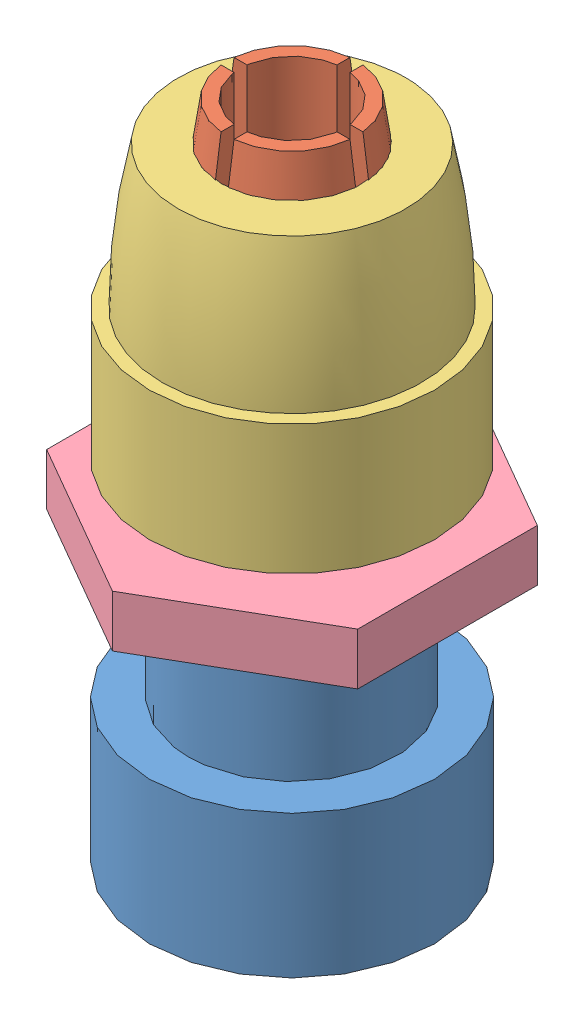
SolidWorks assembly Цанговый зажим, configuration По умолчанию. Lengths in mm.
Overall size (12 25.5 13.86).
4 component instances, 4 part files, 12 mates.
Components (placement in the parent):
- втулка-1: втулка [По умолчанию] at origin size (11 20 11)
- цанга-1: цанга [По умолчанию] at (0 10 0) size (6 15.5 6)
- прижимная гайка-1: прижимная гайка [По умолчанию] at (0 13.5 0) x (-1 0 0) z (0 0 -1) size (11 10.5 11)
- фиксирующая гайка-1: фиксирующая гайка [По умолчанию] at (0 12.5 0) x (1 0 0) z (0 -1 0) size (12 13.86 2)
Mates (geometry in assembly coordinates):
- Совпадение1: coincident anti-aligned: plane of втулка-1 through (5.5 0 0) normal (0 -1 0); plane of assembly through (0 0 0) normal (0 1 0)
- Совпадение2: coincident aligned: plane of втулка-1 through (0 0 0) normal (0 0 1); plane of assembly through (0 0 0) normal (0 0 1)
- Совпадение3: coincident aligned: plane of втулка-1 through (0 0 0) normal (1 0 0); plane of assembly through (0 0 0) normal (1 0 0)
- Концентричный1: concentric anti-aligned: cylinder of втулка-1 through (0 10 0) axis (0 1 0) radius 3; cylinder of цанга-1 through (0 10 0) axis (0 -1 0) radius 3
- Совпадение4: coincident anti-aligned: plane of втулка-1 through (0 10 0) normal (0 1 0); plane of цанга-1 through (3 10 0) normal (0 -1 0)
- Совпадение5: coincident aligned: plane of цанга-1 through (0 10 0) normal (0 0 1); plane of assembly through (0 0 0) normal (0 0 1)
- Концентричный2: concentric aligned: cylinder of втулка-1 through (0 0 0) axis (0 -1 0) radius 4; cylinder of прижимная гайка-1 through (0 17.5 0) axis (0 -1 0) radius 4
- Совпадение6: coincident aligned: cone of цанга-1 through (0 22 0) axis (0 1 0); cone of прижимная гайка-1 through (0 25.5 0) axis (0 1 0)
- Совпадение7: coincident anti-aligned: plane of прижимная гайка-1 through (0 13.5 0) normal (0 0 -1); plane of assembly through (0 0 0) normal (0 0 1)
- Концентричный3: concentric anti-aligned: cylinder of втулка-1 through (0 0 0) axis (0 -1 0) radius 4; cylinder of фиксирующая гайка-1 through (0 10.5 0) axis (0 1 0) radius 4
- Совпадение8: coincident: plane of фиксирующая гайка-1 through (0 10.5 0) normal (0 -1 0); point of assembly
- Совпадение9: coincident aligned: plane of фиксирующая гайка-1; plane of assembly through (0 0 0) normal (1 0 0)
